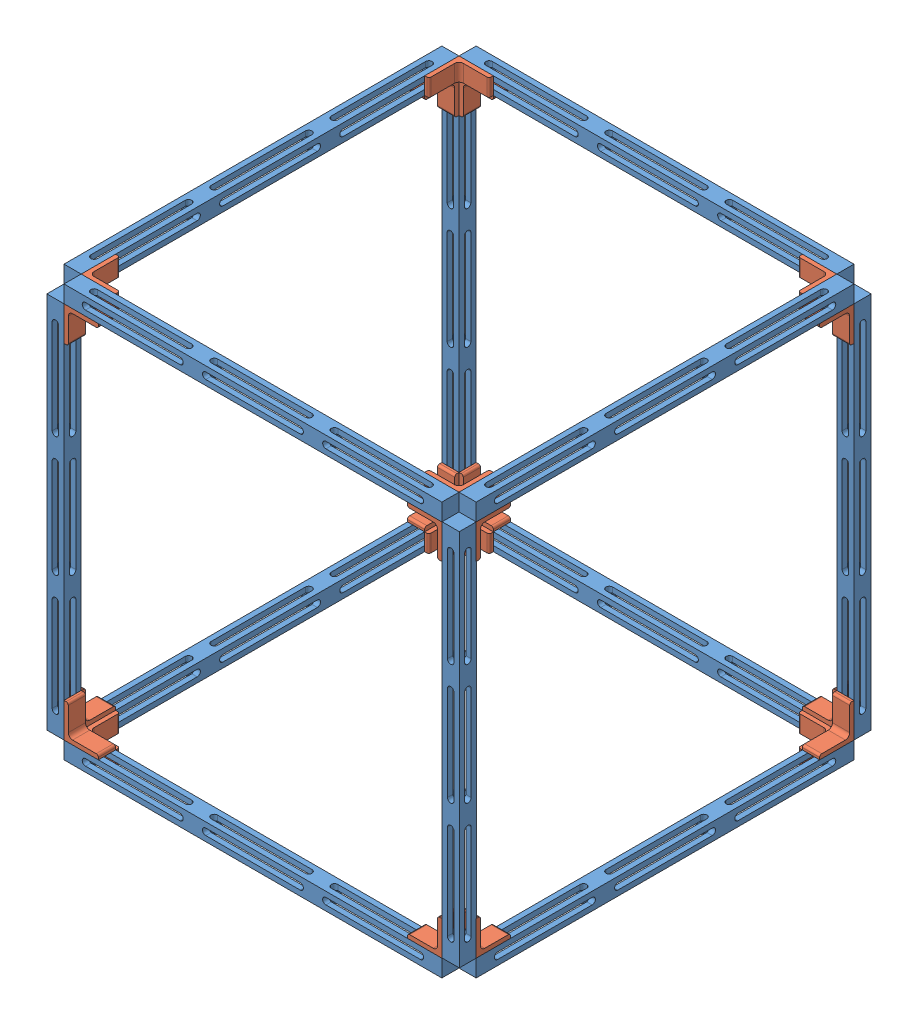
SolidWorks assembly Slotted Cross Proof CAD, configuration Default. Lengths in mm.
Overall size (304.8 304.8 304.8).
36 component instances, 2 part files, 79 mates.
Components (placement in the parent):
- Slot_Strut_11in-1: Slot_Strut_11in [Default] at (211.412 141.8685 310.6728) x (0 1 0) z (0 0 1) size (12.7 279.4 12.7)
- 8982K401_Multipurpose 6061 Aluminum 90 Degree Angle-1: 8982K401_Multipurpose 6061 Aluminum 90 Degree Angle [8982K401] at (-55.288 287.9185 329.7228) x (0 0 -1) z (0 -1 0) size (25.4 25.4 12.7)
- Slot_Strut_11in-2: Slot_Strut_11in [Default] at (-74.338 141.8685 317.0228) x (0 1 0) z (1 0 0) size (12.7 279.4 12.7)
- Slot_Strut_11in-3: Slot_Strut_11in [Default] at (-74.338 148.2185 602.7728) size (12.7 279.4 12.7)
- 8982K401_Multipurpose 6061 Aluminum 90 Degree Angle-2: 8982K401_Multipurpose 6061 Aluminum 90 Degree Angle [8982K401] at (198.712 -4.1815 583.7228) x (1 0 0) z (0 1 0) size (25.4 25.4 12.7)
- Slot_Strut_11in-5: Slot_Strut_11in [Default] at (217.762 141.8685 317.0228) x (0 -1 0) z (-1 0 0) size (12.7 279.4 12.7)
- Slot_Strut_11in-6: Slot_Strut_11in [Default] at (211.412 141.8685 602.7728) x (0 -1 0) z (0 0 -1) size (12.7 279.4 12.7)
- 8982K401_Multipurpose 6061 Aluminum 90 Degree Angle-5: 8982K401_Multipurpose 6061 Aluminum 90 Degree Angle [8982K401] at (-55.288 287.9185 583.7228) x (-1 0 0) z (0 -1 0) size (25.4 25.4 12.7)
- 8982K401_Multipurpose 6061 Aluminum 90 Degree Angle-6: 8982K401_Multipurpose 6061 Aluminum 90 Degree Angle [8982K401] at (198.712 287.9185 329.7228) x (1 0 0) z (0 -1 0) size (25.4 25.4 12.7)
- 8982K401_Multipurpose 6061 Aluminum 90 Degree Angle-7: 8982K401_Multipurpose 6061 Aluminum 90 Degree Angle [8982K401] at (198.712 160.9185 164.6228) size (25.4 25.4 12.7)
- 8982K401_Multipurpose 6061 Aluminum 90 Degree Angle-8: 8982K401_Multipurpose 6061 Aluminum 90 Degree Angle [8982K401] at (-55.288 160.9185 456.7228) x (-1 0 0) z (0 0 -1) size (25.4 25.4 12.7)
- 8982K401_Multipurpose 6061 Aluminum 90 Degree Angle-10: 8982K401_Multipurpose 6061 Aluminum 90 Degree Angle [8982K401] at (198.712 160.9185 456.7228) size (25.4 25.4 12.7)
- 8982K401_Multipurpose 6061 Aluminum 90 Degree Angle-11: 8982K401_Multipurpose 6061 Aluminum 90 Degree Angle [8982K401] at (-55.288 160.9185 748.8228) x (-1 0 0) z (0 0 -1) size (25.4 25.4 12.7)
- 8982K401_Multipurpose 6061 Aluminum 90 Degree Angle-12: 8982K401_Multipurpose 6061 Aluminum 90 Degree Angle [8982K401] at (71.712 160.9185 583.7228) x (0 0 1) z (-1 0 0) size (25.4 25.4 12.7)
- 8982K401_Multipurpose 6061 Aluminum 90 Degree Angle-13: 8982K401_Multipurpose 6061 Aluminum 90 Degree Angle [8982K401] at (-220.388 160.9185 329.7228) x (0 0 -1) z (1 0 0) size (25.4 25.4 12.7)
- 8982K401_Multipurpose 6061 Aluminum 90 Degree Angle-15: 8982K401_Multipurpose 6061 Aluminum 90 Degree Angle [8982K401] at (363.812 160.9185 583.7228) x (0 0 1) z (-1 0 0) size (25.4 25.4 12.7)
- 8982K401_Multipurpose 6061 Aluminum 90 Degree Angle-16: 8982K401_Multipurpose 6061 Aluminum 90 Degree Angle [8982K401] at (71.712 160.9185 329.7228) x (0 0 -1) z (1 0 0) size (25.4 25.4 12.7)
- Slot_Strut_11in-9: Slot_Strut_11in [Default] at (217.762 148.2185 602.5586) size (12.7 279.4 12.7)
- Slot_Strut_11in-10: Slot_Strut_11in [Default] at (-74.338 148.2185 310.6728) size (12.7 279.4 12.7)
- Slot_Strut_11in-11: Slot_Strut_11in [Default] at (217.762 148.2185 310.6728) size (12.7 279.4 12.7)
- 8982K401_Multipurpose 6061 Aluminum 90 Degree Angle-17: 8982K401_Multipurpose 6061 Aluminum 90 Degree Angle [8982K401] at (198.712 287.9185 583.7228) x (1 0 0) z (0 1 0) size (25.4 25.4 12.7)
- Slot_Strut_11in-12: Slot_Strut_11in [Default] at (-67.988 433.9685 602.7728) x (0 1 0) z (0 0 -1) size (12.7 279.4 12.7)
- Slot_Strut_11in-13: Slot_Strut_11in [Default] at (-74.338 433.9685 317.0228) x (0 1 0) z (1 0 0) size (12.7 279.4 12.7)
- 8982K401_Multipurpose 6061 Aluminum 90 Degree Angle-18: 8982K401_Multipurpose 6061 Aluminum 90 Degree Angle [8982K401] at (-55.288 580.0185 583.7228) x (-1 0 0) z (0 -1 0) size (25.4 25.4 12.7)
- Slot_Strut_11in-14: Slot_Strut_11in [Default] at (217.762 433.9685 317.0228) x (0 -1 0) z (-1 0 0) size (12.7 279.4 12.7)
- 8982K401_Multipurpose 6061 Aluminum 90 Degree Angle-19: 8982K401_Multipurpose 6061 Aluminum 90 Degree Angle [8982K401] at (198.712 287.9185 329.7228) x (0 0 -1) z (0 1 0) size (25.4 25.4 12.7)
- Slot_Strut_11in-15: Slot_Strut_11in [Default] at (-67.988 433.9685 310.6728) x (0 -1 0) z (0 0 1) size (12.7 279.4 12.7)
- 8982K401_Multipurpose 6061 Aluminum 90 Degree Angle-20: 8982K401_Multipurpose 6061 Aluminum 90 Degree Angle [8982K401] at (-220.388 414.9185 583.7228) x (0 0 1) z (1 0 0) size (25.4 25.4 12.7)
- 8982K401_Multipurpose 6061 Aluminum 90 Degree Angle-21: 8982K401_Multipurpose 6061 Aluminum 90 Degree Angle [8982K401] at (363.812 414.9185 329.7228) x (0 0 -1) z (-1 0 0) size (25.4 25.4 12.7)
- 8982K401_Multipurpose 6061 Aluminum 90 Degree Angle-22: 8982K401_Multipurpose 6061 Aluminum 90 Degree Angle [8982K401] at (71.712 414.9185 583.7228) x (0 0 1) z (1 0 0) size (25.4 25.4 12.7)
- 8982K401_Multipurpose 6061 Aluminum 90 Degree Angle-23: 8982K401_Multipurpose 6061 Aluminum 90 Degree Angle [8982K401] at (198.712 414.9185 748.8228) x (1 0 0) z (0 0 -1) size (25.4 25.4 12.7)
- 8982K401_Multipurpose 6061 Aluminum 90 Degree Angle-24: 8982K401_Multipurpose 6061 Aluminum 90 Degree Angle [8982K401] at (-55.288 414.9185 456.7228) x (-1 0 0) z (0 0 1) size (25.4 25.4 12.7)
- 8982K401_Multipurpose 6061 Aluminum 90 Degree Angle-25: 8982K401_Multipurpose 6061 Aluminum 90 Degree Angle [8982K401] at (198.712 414.9185 456.7228) x (1 0 0) z (0 0 -1) size (25.4 25.4 12.7)
- 8982K401_Multipurpose 6061 Aluminum 90 Degree Angle-26: 8982K401_Multipurpose 6061 Aluminum 90 Degree Angle [8982K401] at (-55.288 414.9185 164.6228) x (-1 0 0) z (0 0 1) size (25.4 25.4 12.7)
- 8982K401_Multipurpose 6061 Aluminum 90 Degree Angle-27: 8982K401_Multipurpose 6061 Aluminum 90 Degree Angle [8982K401] at (-55.288 287.9185 329.7228) x (-1 0 0) z (0 1 0) size (25.4 25.4 12.7)
- 8982K401_Multipurpose 6061 Aluminum 90 Degree Angle-28: 8982K401_Multipurpose 6061 Aluminum 90 Degree Angle [8982K401] at (-220.388 414.9185 329.7228) x (0 1 0) z (1 0 0) size (25.4 25.4 12.7)
Mates (geometry in assembly coordinates):
- Coincident8: coincident aligned: line of Slot_Strut_11in-1 through (-67.988 135.5185 317.0228) axis (0 1 0); line of 8982K401_Multipurpose 6061 Aluminum 90 Degree Angle-1 through (-67.988 135.5185 317.0228) axis (0 1 0)
- Coincident9: coincident aligned: line of Slot_Strut_11in-1 through (-67.988 148.2185 317.0228) axis (1 0 0); line of 8982K401_Multipurpose 6061 Aluminum 90 Degree Angle-1 through (-67.988 148.2185 317.0228) axis (1 0 0)
- Coincident10: coincident aligned: line of 8982K401_Multipurpose 6061 Aluminum 90 Degree Angle-1 through (-67.988 135.5185 317.0228) axis (0 1 0); line of Slot_Strut_11in-2 through (-67.988 135.5185 317.0228) axis (0 1 0)
- Coincident11: coincident anti-aligned: line of 8982K401_Multipurpose 6061 Aluminum 90 Degree Angle-1 through (-67.988 148.2185 317.0228) axis (0 0 1); line of Slot_Strut_11in-2 through (-67.988 148.2185 596.4228) axis (0 0 -1)
- Coincident12: coincident aligned: line of 8982K401_Multipurpose 6061 Aluminum 90 Degree Angle-2 through (211.412 148.2185 596.4228) axis (0 -1 0); line of Slot_Strut_11in-5 through (211.412 148.2185 596.4228) axis (0 -1 0)
- Coincident13: coincident aligned: line of 8982K401_Multipurpose 6061 Aluminum 90 Degree Angle-2 through (211.412 135.5185 596.4228) axis (0 0 -1); line of Slot_Strut_11in-5 through (211.412 135.5185 596.4228) axis (0 0 -1)
- Coincident14: coincident anti-aligned: line of 8982K401_Multipurpose 6061 Aluminum 90 Degree Angle-2 through (211.412 135.5185 596.4228) axis (-1 0 0); line of Slot_Strut_11in-6 through (-67.988 135.5185 596.4228) axis (1 0 0)
- Coincident15: coincident aligned: line of 8982K401_Multipurpose 6061 Aluminum 90 Degree Angle-2 through (211.412 148.2185 596.4228) axis (0 -1 0); line of Slot_Strut_11in-6 through (211.412 148.2185 596.4228) axis (0 -1 0)
- Coincident23: coincident aligned: line of Slot_Strut_11in-2 through (-67.988 148.2185 596.4228) axis (0 0 -1); line of 8982K401_Multipurpose 6061 Aluminum 90 Degree Angle-5 through (-67.988 148.2185 596.4228) axis (0 0 -1)
- Coincident24: coincident aligned: line of Slot_Strut_11in-2 through (-67.988 135.5185 596.4228) axis (0 1 0); line of 8982K401_Multipurpose 6061 Aluminum 90 Degree Angle-5 through (-67.988 135.5185 596.4228) axis (0 1 0)
- Coincident25: coincident anti-aligned: line of Slot_Strut_11in-1 through (-67.988 148.2185 317.0228) axis (1 0 0); line of 8982K401_Multipurpose 6061 Aluminum 90 Degree Angle-6 through (211.412 148.2185 317.0228) axis (-1 0 0)
- Coincident26: coincident aligned: line of Slot_Strut_11in-1 through (211.412 135.5185 317.0228) axis (0 1 0); line of 8982K401_Multipurpose 6061 Aluminum 90 Degree Angle-6 through (211.412 135.5185 317.0228) axis (0 1 0)
- Coincident27: coincident anti-aligned: line of Slot_Strut_11in-6 through (-67.988 148.2185 596.4228) axis (0 -1 0); line of 8982K401_Multipurpose 6061 Aluminum 90 Degree Angle-5 through (-67.988 135.5185 596.4228) axis (0 1 0)
- Coincident28: coincident anti-aligned: line of Slot_Strut_11in-1 through (211.412 135.5185 317.0228) axis (0 1 0); line of Slot_Strut_11in-5 through (211.412 148.2185 317.0228) axis (0 -1 0)
- Coincident29: coincident aligned: line of Slot_Strut_11in-6 through (-67.988 148.2185 596.4228) axis (1 0 0); line of 8982K401_Multipurpose 6061 Aluminum 90 Degree Angle-5 through (-67.988 148.2185 596.4228) axis (1 0 0)
- Coincident30: coincident aligned: line of Slot_Strut_11in-1 through (211.412 148.2185 317.0228) axis (0 0 -1); line of 8982K401_Multipurpose 6061 Aluminum 90 Degree Angle-7 through (211.412 148.2185 317.0228) axis (0 0 -1)
- Coincident32: coincident aligned: line of Slot_Strut_11in-6 through (-67.988 148.2185 609.1228) axis (1 0 0); line of 8982K401_Multipurpose 6061 Aluminum 90 Degree Angle-10 through (186.012 148.2185 609.1228) axis (1 0 0)
- Coincident33: coincident aligned: line of Slot_Strut_11in-6 through (-67.988 148.2185 609.1228) axis (1 0 0); line of 8982K401_Multipurpose 6061 Aluminum 90 Degree Angle-11 through (-67.988 148.2185 609.1228) axis (1 0 0)
- Coincident34: coincident anti-aligned: line of Slot_Strut_11in-6 through (-67.988 148.2185 609.1228) axis (0 0 -1); line of 8982K401_Multipurpose 6061 Aluminum 90 Degree Angle-11 through (-67.988 148.2185 596.4228) axis (0 0 1)
- Coincident35: coincident aligned: line of Slot_Strut_11in-6 through (211.412 148.2185 609.1228) axis (0 0 -1); line of 8982K401_Multipurpose 6061 Aluminum 90 Degree Angle-10 through (211.412 148.2185 609.1228) axis (0 0 -1)
- Coincident38: coincident aligned: line of Slot_Strut_11in-1 through (-67.988 148.2185 317.0228) axis (1 0 0); line of 8982K401_Multipurpose 6061 Aluminum 90 Degree Angle-8 through (-67.988 148.2185 317.0228) axis (1 0 0)
- Coincident39: coincident anti-aligned: line of Slot_Strut_11in-1 through (-67.988 148.2185 317.0228) axis (0 0 -1); line of 8982K401_Multipurpose 6061 Aluminum 90 Degree Angle-8 through (-67.988 148.2185 304.3228) axis (0 0 1)
- Coincident40: coincident aligned: line of Slot_Strut_11in-5 through (224.112 148.2185 596.4228) axis (0 0 -1); line of 8982K401_Multipurpose 6061 Aluminum 90 Degree Angle-15 through (224.112 148.2185 596.4228) axis (0 0 -1)
- Coincident41: coincident anti-aligned: line of Slot_Strut_11in-5 through (224.112 148.2185 596.4228) axis (-1 0 0); line of 8982K401_Multipurpose 6061 Aluminum 90 Degree Angle-15 through (211.412 148.2185 596.4228) axis (1 0 0)
- Coincident44: coincident aligned: line of Slot_Strut_11in-5 through (224.112 148.2185 596.4228) axis (0 0 -1); line of 8982K401_Multipurpose 6061 Aluminum 90 Degree Angle-16 through (224.112 148.2185 342.4228) axis (0 0 -1)
- Coincident45: coincident aligned: line of Slot_Strut_11in-5 through (224.112 148.2185 317.0228) axis (-1 0 0); line of 8982K401_Multipurpose 6061 Aluminum 90 Degree Angle-16 through (224.112 148.2185 317.0228) axis (-1 0 0)
- Coincident46: coincident anti-aligned: line of Slot_Strut_11in-1 through (-67.988 148.2185 304.3228) axis (1 0 0); line of 8982K401_Multipurpose 6061 Aluminum 90 Degree Angle-7 through (211.412 148.2185 304.3228) axis (-1 0 0)
- Coincident47: coincident anti-aligned: line of Slot_Strut_11in-2 through (-67.988 148.2185 596.4228) axis (-1 0 0); line of 8982K401_Multipurpose 6061 Aluminum 90 Degree Angle-12 through (-80.688 148.2185 596.4228) axis (1 0 0)
- Coincident48: coincident aligned: line of Slot_Strut_11in-2 through (-67.988 148.2185 596.4228) axis (0 0 -1); line of 8982K401_Multipurpose 6061 Aluminum 90 Degree Angle-12 through (-67.988 148.2185 596.4228) axis (0 0 -1)
- Coincident49: coincident aligned: line of Slot_Strut_11in-2 through (-67.988 148.2185 317.0228) axis (-1 0 0); line of 8982K401_Multipurpose 6061 Aluminum 90 Degree Angle-13 through (-67.988 148.2185 317.0228) axis (-1 0 0)
- Coincident50: coincident anti-aligned: line of Slot_Strut_11in-2 through (-80.688 148.2185 596.4228) axis (0 0 -1); line of 8982K401_Multipurpose 6061 Aluminum 90 Degree Angle-13 through (-80.688 148.2185 317.0228) axis (0 0 1)
- Coincident51: coincident anti-aligned: line of 8982K401_Multipurpose 6061 Aluminum 90 Degree Angle-7 through (211.412 148.2185 317.0228) axis (0 0 -1); line of Slot_Strut_11in-11 through (211.412 148.2185 304.3228) axis (0 0 1)
- Coincident52: coincident anti-aligned: line of 8982K401_Multipurpose 6061 Aluminum 90 Degree Angle-16 through (224.112 148.2185 317.0228) axis (-1 0 0); line of Slot_Strut_11in-11 through (211.412 148.2185 317.0228) axis (1 0 0)
- Coincident53: coincident anti-aligned: line of 8982K401_Multipurpose 6061 Aluminum 90 Degree Angle-8 through (-67.988 148.2185 304.3228) axis (0 0 1); line of Slot_Strut_11in-10 through (-67.988 148.2185 317.0228) axis (0 0 -1)
- Coincident54: coincident anti-aligned: line of 8982K401_Multipurpose 6061 Aluminum 90 Degree Angle-13 through (-67.988 148.2185 317.0228) axis (-1 0 0); line of Slot_Strut_11in-10 through (-80.688 148.2185 317.0228) axis (1 0 0)
- Coincident55: coincident anti-aligned: line of Slot_Strut_11in-3 through (-67.988 148.2185 609.1228) axis (0 0 -1); line of 8982K401_Multipurpose 6061 Aluminum 90 Degree Angle-11 through (-67.988 148.2185 596.4228) axis (0 0 1)
- Coincident56: coincident anti-aligned: line of Slot_Strut_11in-3 through (-67.988 148.2185 596.4228) axis (-1 0 0); line of 8982K401_Multipurpose 6061 Aluminum 90 Degree Angle-12 through (-80.688 148.2185 596.4228) axis (1 0 0)
- Coincident57: coincident: line of Slot_Strut_11in-6 through (211.412 148.2185 609.1228) axis (0 0 -1); line of Slot_Strut_11in-9 through (211.8576 148.319 596.2086) axis (0 0 1)
- Coincident58: coincident anti-aligned: line of 8982K401_Multipurpose 6061 Aluminum 90 Degree Angle-15 through (211.412 148.2185 596.4228) axis (1 0 0); line of Slot_Strut_11in-5 through (224.112 148.2185 596.4228) axis (-1 0 0)
- Coincident59: coincident aligned: line of 8982K401_Multipurpose 6061 Aluminum 90 Degree Angle-19 through (211.412 440.3185 317.0228) axis (0 -1 0); line of Slot_Strut_11in-15 through (211.412 440.3185 317.0228) axis (0 -1 0)
- Coincident60: coincident aligned: line of 8982K401_Multipurpose 6061 Aluminum 90 Degree Angle-19 through (211.412 427.6185 317.0228) axis (-1 0 0); line of Slot_Strut_11in-15 through (211.412 427.6185 317.0228) axis (-1 0 0)
- Coincident61: coincident anti-aligned: line of Slot_Strut_11in-13 through (-80.688 427.6185 596.4228) axis (1 0 0); line of 8982K401_Multipurpose 6061 Aluminum 90 Degree Angle-20 through (-67.988 427.6185 596.4228) axis (-1 0 0)
- Coincident62: coincident anti-aligned: line of Slot_Strut_11in-14 through (211.412 427.6185 596.4228) axis (0 0 -1); line of 8982K401_Multipurpose 6061 Aluminum 90 Degree Angle-19 through (211.412 427.6185 317.0228) axis (0 0 1)
- Coincident63: coincident anti-aligned: line of Slot_Strut_11in-12 through (211.412 440.3185 596.4228) axis (-1 0 0); line of 8982K401_Multipurpose 6061 Aluminum 90 Degree Angle-18 through (-67.988 440.3185 596.4228) axis (1 0 0)
- Coincident64: coincident aligned: line of Slot_Strut_11in-12 through (-67.988 427.6185 596.4228) axis (0 1 0); line of 8982K401_Multipurpose 6061 Aluminum 90 Degree Angle-18 through (-67.988 427.6185 596.4228) axis (0 1 0)
- Coincident65: coincident aligned: line of Slot_Strut_11in-13 through (-67.988 427.6185 596.4228) axis (0 1 0); line of 8982K401_Multipurpose 6061 Aluminum 90 Degree Angle-18 through (-67.988 427.6185 596.4228) axis (0 1 0)
- Coincident66: coincident aligned: line of Slot_Strut_11in-14 through (211.412 440.3185 317.0228) axis (0 -1 0); line of 8982K401_Multipurpose 6061 Aluminum 90 Degree Angle-19 through (211.412 440.3185 317.0228) axis (0 -1 0)
- Coincident67: coincident aligned: line of Slot_Strut_11in-13 through (-67.988 440.3185 596.4228) axis (0 0 -1); line of 8982K401_Multipurpose 6061 Aluminum 90 Degree Angle-18 through (-67.988 440.3185 596.4228) axis (0 0 -1)
- Coincident68: coincident anti-aligned: line of Slot_Strut_11in-13 through (-80.688 427.6185 596.4228) axis (1 0 0); line of 8982K401_Multipurpose 6061 Aluminum 90 Degree Angle-20 through (-67.988 427.6185 596.4228) axis (-1 0 0)
- Coincident69: coincident anti-aligned: line of Slot_Strut_11in-14 through (211.412 427.6185 596.4228) axis (1 0 0); line of 8982K401_Multipurpose 6061 Aluminum 90 Degree Angle-22 through (224.112 427.6185 596.4228) axis (-1 0 0)
- Coincident70: coincident anti-aligned: line of Slot_Strut_11in-15 through (211.412 427.6185 317.0228) axis (0 0 -1); line of 8982K401_Multipurpose 6061 Aluminum 90 Degree Angle-25 through (211.412 427.6185 304.3228) axis (0 0 1)
- Coincident71: coincident aligned: line of Slot_Strut_11in-15 through (211.412 427.6185 317.0228) axis (-1 0 0); line of 8982K401_Multipurpose 6061 Aluminum 90 Degree Angle-25 through (211.412 427.6185 317.0228) axis (-1 0 0)
- Coincident72: coincident aligned: line of Slot_Strut_11in-12 through (-67.988 427.6185 609.1228) axis (0 0 -1); line of 8982K401_Multipurpose 6061 Aluminum 90 Degree Angle-24 through (-67.988 427.6185 609.1228) axis (0 0 -1)
- Coincident73: coincident aligned: line of Slot_Strut_11in-12 through (211.412 427.6185 609.1228) axis (-1 0 0); line of 8982K401_Multipurpose 6061 Aluminum 90 Degree Angle-24 through (-42.588 427.6185 609.1228) axis (-1 0 0)
- Coincident74: coincident anti-aligned: line of Slot_Strut_11in-12 through (211.412 427.6185 609.1228) axis (0 0 -1); line of 8982K401_Multipurpose 6061 Aluminum 90 Degree Angle-23 through (211.412 427.6185 596.4228) axis (0 0 1)
- Coincident75: coincident aligned: line of Slot_Strut_11in-12 through (211.412 427.6185 609.1228) axis (-1 0 0); line of 8982K401_Multipurpose 6061 Aluminum 90 Degree Angle-23 through (211.412 427.6185 609.1228) axis (-1 0 0)
- Coincident76: coincident aligned: line of Slot_Strut_11in-13 through (-80.688 427.6185 596.4228) axis (0 0 -1); line of 8982K401_Multipurpose 6061 Aluminum 90 Degree Angle-20 through (-80.688 427.6185 596.4228) axis (0 0 -1)
- Coincident77: coincident anti-aligned: line of Slot_Strut_11in-15 through (211.412 427.6185 304.3228) axis (-1 0 0); line of 8982K401_Multipurpose 6061 Aluminum 90 Degree Angle-26 through (-67.988 427.6185 304.3228) axis (1 0 0)
- Coincident78: coincident aligned: line of Slot_Strut_11in-14 through (211.412 427.6185 317.0228) axis (1 0 0); line of 8982K401_Multipurpose 6061 Aluminum 90 Degree Angle-21 through (211.412 427.6185 317.0228) axis (1 0 0)
- Coincident79: coincident anti-aligned: line of Slot_Strut_11in-14 through (224.112 427.6185 596.4228) axis (0 0 -1); line of 8982K401_Multipurpose 6061 Aluminum 90 Degree Angle-21 through (224.112 427.6185 317.0228) axis (0 0 1)
- Coincident80: coincident aligned: line of Slot_Strut_11in-14 through (211.412 427.6185 596.4228) axis (0 0 -1); line of 8982K401_Multipurpose 6061 Aluminum 90 Degree Angle-22 through (211.412 427.6185 596.4228) axis (0 0 -1)
- Coincident81: coincident aligned: line of 8982K401_Multipurpose 6061 Aluminum 90 Degree Angle-17 through (211.412 427.6185 596.4228) axis (0 0 -1); line of Slot_Strut_11in-14 through (211.412 427.6185 596.4228) axis (0 0 -1)
- Coincident82: coincident aligned: line of Slot_Strut_11in-15 through (-67.988 427.6185 317.0228) axis (0 0 -1); line of 8982K401_Multipurpose 6061 Aluminum 90 Degree Angle-26 through (-67.988 427.6185 317.0228) axis (0 0 -1)
- Coincident83: coincident aligned: line of 8982K401_Multipurpose 6061 Aluminum 90 Degree Angle-17 through (211.412 440.3185 596.4228) axis (0 -1 0); line of Slot_Strut_11in-14 through (211.412 440.3185 596.4228) axis (0 -1 0)
- Coincident84: coincident aligned: line of Slot_Strut_11in-15 through (-67.988 440.3185 317.0228) axis (0 -1 0); line of 8982K401_Multipurpose 6061 Aluminum 90 Degree Angle-27 through (-67.988 440.3185 317.0228) axis (0 -1 0)
- Coincident85: coincident anti-aligned: line of 8982K401_Multipurpose 6061 Aluminum 90 Degree Angle-17 through (211.412 440.3185 596.4228) axis (0 -1 0); line of Slot_Strut_11in-12 through (211.412 427.6185 596.4228) axis (0 1 0)
- Coincident86: coincident anti-aligned: line of Slot_Strut_11in-13 through (-67.988 427.6185 317.0228) axis (0 1 0); line of Slot_Strut_11in-15 through (-67.988 440.3185 317.0228) axis (0 -1 0)
- Coincident87: coincident anti-aligned: line of Slot_Strut_11in-15 through (211.412 427.6185 317.0228) axis (-1 0 0); line of 8982K401_Multipurpose 6061 Aluminum 90 Degree Angle-27 through (-67.988 427.6185 317.0228) axis (1 0 0)
- Coincident88: coincident aligned: line of 8982K401_Multipurpose 6061 Aluminum 90 Degree Angle-17 through (211.412 427.6185 596.4228) axis (-1 0 0); line of Slot_Strut_11in-12 through (211.412 427.6185 596.4228) axis (-1 0 0)
- Coincident89: coincident anti-aligned: line of Slot_Strut_11in-13 through (-80.688 427.6185 317.0228) axis (1 0 0); line of 8982K401_Multipurpose 6061 Aluminum 90 Degree Angle-28 through (-67.988 427.6185 317.0228) axis (-1 0 0)
- Coincident90: coincident anti-aligned: line of Slot_Strut_11in-13 through (-80.688 427.6185 596.4228) axis (0 0 -1); line of 8982K401_Multipurpose 6061 Aluminum 90 Degree Angle-28 through (-80.688 427.6185 317.0228) axis (0 0 1)
- Coincident91: coincident aligned: line of Slot_Strut_11in-10 through (-80.688 427.6185 317.0228) axis (1 0 0); line of Slot_Strut_11in-13 through (-80.688 427.6185 317.0228) axis (1 0 0)
- Coincident92: coincident aligned: line of Slot_Strut_11in-10 through (-67.988 427.6185 317.0228) axis (0 0 -1); line of Slot_Strut_11in-15 through (-67.988 427.6185 317.0228) axis (0 0 -1)
- Coincident93: coincident aligned: line of Slot_Strut_11in-11 through (211.412 427.6185 304.3228) axis (0 0 1); line of 8982K401_Multipurpose 6061 Aluminum 90 Degree Angle-25 through (211.412 427.6185 304.3228) axis (0 0 1)
- Coincident94: coincident: line of Slot_Strut_11in-9 through (211.8576 427.719 596.2086) axis (0 0 1); line of 8982K401_Multipurpose 6061 Aluminum 90 Degree Angle-23 through (211.412 427.6185 596.4228) axis (0 0 1)
- Coincident95: coincident anti-aligned: line of Slot_Strut_11in-14 through (211.412 427.6185 596.4228) axis (1 0 0); line of 8982K401_Multipurpose 6061 Aluminum 90 Degree Angle-22 through (224.112 427.6185 596.4228) axis (-1 0 0)
- Coincident96: coincident anti-aligned: line of Slot_Strut_11in-13 through (-80.688 427.6185 596.4228) axis (1 0 0); line of 8982K401_Multipurpose 6061 Aluminum 90 Degree Angle-20 through (-67.988 427.6185 596.4228) axis (-1 0 0)
- Coincident97: coincident aligned: line of Slot_Strut_11in-12 through (-67.988 427.6185 609.1228) axis (0 0 -1); line of 8982K401_Multipurpose 6061 Aluminum 90 Degree Angle-24 through (-67.988 427.6185 609.1228) axis (0 0 -1)
- Coincident98: coincident: plane of Slot_Strut_11in-9 through (217.762 427.6185 602.5586) normal (0 1 0); line of Slot_Strut_11in-14 through (211.412 427.6185 596.4228) axis (1 0 0)
